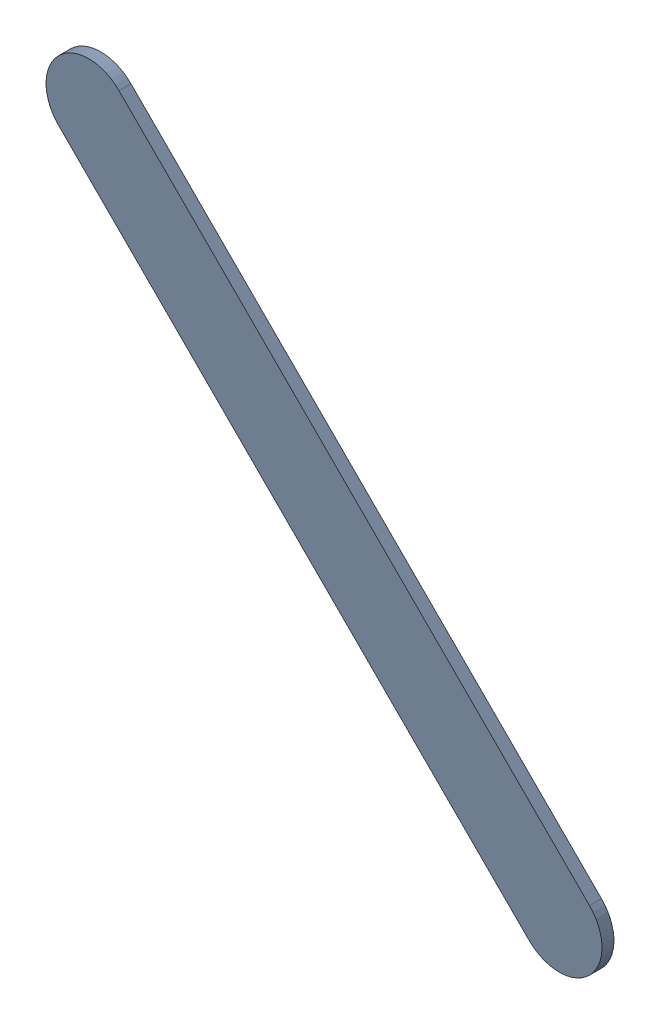
SolidWorks assembly Track (23mm,54.9mm)(24.4mm,53.5mm) on Top Layer, configuration Predeterminado. Lengths in mm.
Overall size (1.65 1.65 0.04).
2 component instances, 1 part files, 0 mates.
Components (placement in the parent):
- Track (23mm,54.9mm)(24.4mm,53.5mm) on Top Layer-1-1: Track (23mm,54.9mm)(24.4mm,53.5mm) on Top Layer-1 [Predeterminado] at (-68.317 -44.187 -0.0457) size (1.65 1.65 0.04)
  - Track (23mm,54.9mm)(24.4mm,53.5mm) on Top Layer-Part-1-1: Track (23mm,54.9mm)(24.4mm,53.5mm) on Top Layer-Part-1 [Predeterminado] at origin size (1.65 1.65 0.04)
